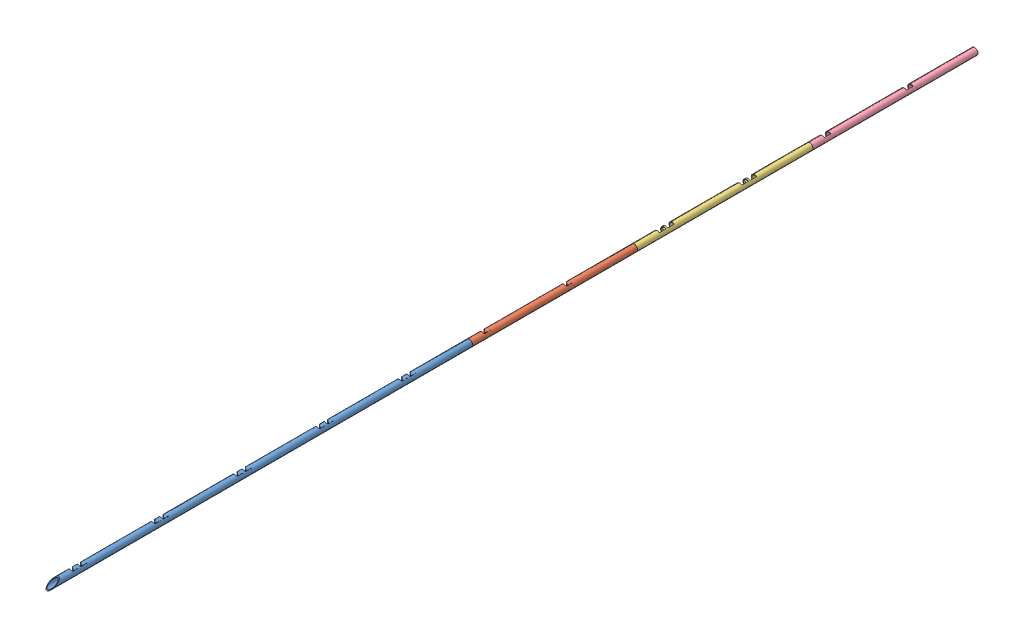
SolidWorks assembly ANSTY_1DOF_Square and Modified Joints, configuration Default. Lengths in mm.
Overall size (1.25 1.49 173.57).
4 component instances, 4 part files, 7 mates.
Components (placement in the parent):
- Arushri_Tube_MultiJoint-1: Arushri_Tube_MultiJoint [Default] at (23.3613 39.1781 97.3022) size (1.25 1.49 79.02)
- Arushri_Tube_ModifiedSingleJoint-1: Arushri_Tube_ModifiedSingleJoint [Default] at (23.3613 39.1781 21.8362) size (1.25 1.49 30.87)
- Arushri_Tube_SquareJoint-1: Arushri_Tube_SquareJoint [Default] at (23.3613 39.1781 -12.5848) size (1.24 1.24 32.82)
- Arushri_Tube_SingleSquareJoint-1: Arushri_Tube_SingleSquareJoint [Default] at (23.3613 39.1781 -41.8508) size (1.24 1.24 30.87)
Mates (geometry in assembly coordinates):
- Coincident1: coincident anti-aligned: plane of Arushri_Tube_MultiJoint-1 through (23.3613 39.1781 25.7022) normal (0 0 -1); plane of Arushri_Tube_ModifiedSingleJoint-1 through (23.3613 39.1781 25.7022) normal (0 0 1)
- Coincident2: coincident anti-aligned: circle of Arushri_Tube_MultiJoint-1; circle of Arushri_Tube_ModifiedSingleJoint-1
- Coincident3: coincident anti-aligned: plane of Arushri_Tube_ModifiedSingleJoint-1 through (23.3613 39.1781 -5.1638) normal (0 0 -1); plane of Arushri_Tube_SquareJoint-1 through (23.3613 39.1781 -5.1638) normal (0 0 1)
- Coincident4: coincident aligned: circle of Arushri_Tube_ModifiedSingleJoint-1; circle of Arushri_Tube_SquareJoint-1
- Coincident5: coincident anti-aligned: plane of Arushri_Tube_SquareJoint-1 through (23.3613 39.1781 -37.9848) normal (0 0 -1); plane of Arushri_Tube_SingleSquareJoint-1 through (23.3613 39.1781 -37.9848) normal (0 0 1)
- Coincident6: coincident anti-aligned: plane of Arushri_Tube_SquareJoint-1 through (23.3613 39.1781 -37.9848) normal (0 0 -1); plane of Arushri_Tube_SingleSquareJoint-1 through (23.3613 39.1781 -37.9848) normal (0 0 1)
- Coincident7: coincident anti-aligned: circle of Arushri_Tube_SquareJoint-1; circle of Arushri_Tube_SingleSquareJoint-1
